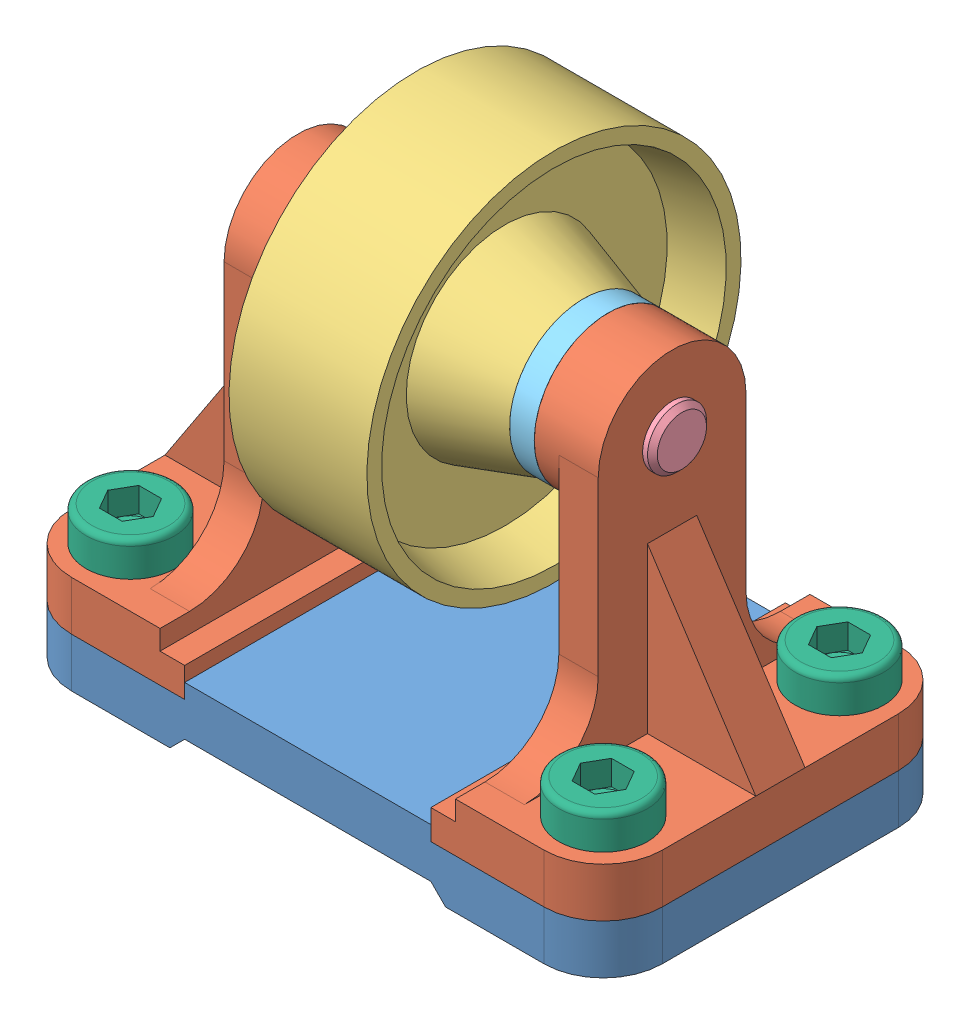
SolidWorks assembly Belt roller assembly, configuration Default. Lengths in mm.
Overall size (120 123.55 107.1).
11 component instances, 6 part files, 18 mates.
Components (placement in the parent):
- 1.Base-1: 1.Base [Default] at origin size (120 13 72)
- 2.Bracket-1: 2.Bracket [Default] at (-42.5 10 0) x (0 0 1) z (-1 0 0) size (72 75 35)
- 2.Bracket-2: 2.Bracket [Default] at (42.5 10 0) x (0 0 -1) z (1 0 0) size (72 75 35)
- 3.Roller-1: 3.Roller [Default] at (0 70 0) x (1 0 0) z (0 -0.645156 0.764051) size (40 76 76)
- 5.Shaft-1: 5.Shaft [Default] at (-40 70 0) size (80 18 18)
- 4.Bush-1: 4.Bush [Default] at (-25 70 0) size (21 30 30)
- 4.Bush-2: 4.Bush [Default] at (25 70 0) x (-1 0 0) z (0 0 -1) size (21 30 30)
- socket head thin cap screw_din-1: socket head thin cap screw_din [DIN 7984 - M12 x 20 --- 14.75C] at (-48 27 24) x (0 -1 0) z (0 0 1) size (27 18 18)
- socket head thin cap screw_din-2: socket head thin cap screw_din [DIN 7984 - M12 x 20 --- 14.75C] at (48 27 24) x (0 -1 0) z (0 0 1) size (27 18 18)
- socket head thin cap screw_din-3: socket head thin cap screw_din [DIN 7984 - M12 x 20 --- 14.75C] at (48 27 -24) x (0 -1 0) z (0 0 1) size (27 18 18)
- socket head thin cap screw_din-4: socket head thin cap screw_din [DIN 7984 - M12 x 20 --- 14.75C] at (-48 27 -24) x (0 -1 0) z (0 0 1) size (27 18 18)
Mates (geometry in assembly coordinates):
- Coincident3: coordinate: point of 1.Base-1
- Concentric1: concentric aligned: circle of 1.Base-1; circle of 2.Bracket-1
- Concentric2: concentric aligned: circle of 1.Base-1; circle of 2.Bracket-1
- Coincident6: coincident anti-aligned: plane of 1.Base-1 through (0 10 0) normal (0 1 0); plane of 2.Bracket-1 through (-42.5 10 0) normal (0 -1 0)
- Concentric3: concentric anti-aligned: cylinder of 3.Roller-1 through (90.0086 70 0) axis (1 0 0) radius 12; cylinder of 5.SHaft-1 through (-40 70 0) axis (-1 0 0) radius 9
- Width1: width aligned: plane of 3.Roller-1 through (14 96.7418 22.5805) normal (1 0 0); plane of 3.Roller-1 through (-14 96.7418 22.5805) normal (-1 0 0); plane of 5.SHaft-1 through (40 70 0) normal (1 0 0); plane of 5.SHaft-1 through (-40 76 0) normal (-1 0 0)
- Concentric4: concentric anti-aligned: cylinder of 2.Bracket-1 through (-38 70 0) axis (1 0 0) radius 6; cylinder of 5.SHaft-1 through (-40 70 0) axis (-1 0 0) radius 6
- Width2: width anti-aligned: plane of 5.SHaft-1 through (40 70 0) normal (1 0 0); plane of 5.SHaft-1 through (-40 76 0) normal (-1 0 0); plane of 2.Bracket-1 through (-38 70 0) normal (-1 0 0); plane of 2.Bracket-2 through (38 70 0) normal (1 0 0)
- Concentric5: concentric aligned: cylinder of 5.SHaft-1 through (-40 70 0) axis (-1 0 0) radius 9; cylinder of 4.Bush-1 through (-25 70 0) axis (-1 0 0) radius 12
- Coincident7: coincident anti-aligned: plane of 3.Roller-1 through (-20 79.1686 7.7419) normal (-1 0 0); plane of 4.Bush-1 through (-20 85 0) normal (1 0 0)
- Concentric6: concentric aligned: cylinder of 2.Bracket-1 through (-48 20 24) axis (0 1 0) radius 5.1; cylinder of socket head thin cap screw_din-1 through (-48 58.75 24) axis (0 1 0) radius 9
- Coincident8: coincident anti-aligned: plane of 2.Bracket-1 through (-42.5 20 0) normal (0 1 0); plane of socket head thin cap screw_din-1 through (-39 20 24) normal (0 -1 0)
- Concentric7: concentric aligned: cylinder of 2.Bracket-2 through (48 20 24) axis (0 1 0) radius 5.1; cylinder of socket head thin cap screw_din-2 through (48 58.75 24) axis (0 1 0) radius 9
- Coincident9: coincident anti-aligned: plane of 2.Bracket-2 through (42.5 20 0) normal (0 1 0); plane of socket head thin cap screw_din-2 through (57 20 24) normal (0 -1 0)
- Concentric8: concentric aligned: cylinder of 2.Bracket-2 through (48 20 -24) axis (0 1 0) radius 5.1; cylinder of socket head thin cap screw_din-3 through (48 58.75 -24) axis (0 1 0) radius 9
- Coincident10: coincident anti-aligned: plane of 2.Bracket-2 through (42.5 20 0) normal (0 1 0); plane of socket head thin cap screw_din-3 through (57 20 -24) normal (0 -1 0)
- Concentric9: concentric aligned: cylinder of 2.Bracket-1 through (-48 20 -24) axis (0 1 0) radius 5.1; cylinder of socket head thin cap screw_din-4 through (-48 58.75 -24) axis (0 1 0) radius 9
- Coincident11: coincident anti-aligned: plane of 2.Bracket-1 through (-42.5 20 0) normal (0 1 0); plane of socket head thin cap screw_din-4 through (-39 20 -24) normal (0 -1 0)
